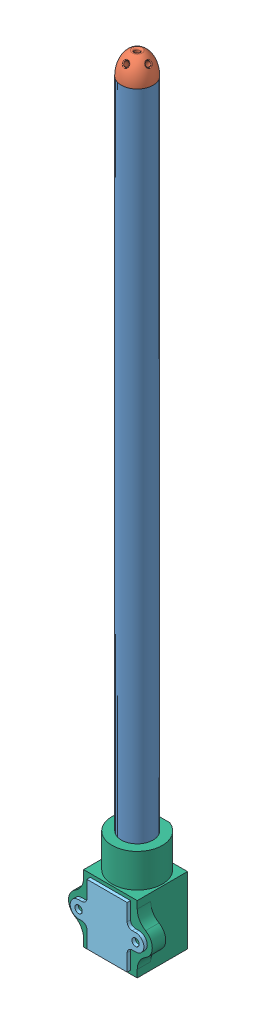
SolidWorks assembly flow-sensor, configuration Default. Lengths in mm.
Overall size (25 231.71 16).
9 component instances, 6 part files, 6 mates.
Components (placement in the parent):
- flow-sensor-tube-1: flow-sensor-tube [Default] at origin size (9.5 200 9.5)
- flow-sensor-tip-1: flow-sensor-tip [Default] at (0 200 0) x (1 0 0) z (0 -1 0) size (9.5 9.5 9.71)
- pressure_board-1: pressure_board [Default] at (0 -15 8) x (0 1 0) z (-1 0 0) size (30 16 25)
  - sdp3x-1: sdp3x [Default] at (4.5 0 3) size (8.5 4.4 5.5)
  - sdp3x-2: sdp3x [Default] at (4.5 0 -3) x (-1 0 0) z (0 0 -1) size (8.5 4.4 5.5)
  - sdp3x-3: sdp3x [Default] at (-4.5 0 3) size (8.5 4.4 5.5)
  - static_pressure_connector-1: static_pressure_connector [Default] at (-4.5 0 -3) size (8 6.1 9.55)
  - PCB^pressure_board-1: PCB^pressure_board [Default] at origin size (18 1 22) (virtual)
  - Part2^pressure_board-1: Part2^pressure_board [Default] at origin size (30 15 25) (virtual)
Mates (geometry in assembly coordinates):
- Coincident1: coincident anti-aligned: circle of flow-sensor-tube-1; circle of flow-sensor-tip-1
- Concentric1: concentric anti-aligned: cylinder of flow-sensor-tube-1 through (0 200 0) axis (0 -1 0) radius 4.75; cylinder of pressure_board-1/Part2^pressure_board-1 through (0 -19.435 0) axis (0 1 0) radius 4.75
- Coincident2: coincident anti-aligned: plane of flow-sensor-tube-1 through (0 0 0) normal (0 -1 0); plane of pressure_board-1/Part2^pressure_board-1 through (5.6615 0 1.9869) normal (0 1 0)
- Coincident3: coordinate: point of flow-sensor-tube-1; point of assembly
- Coincident4: coincident aligned: plane of flow-sensor-tip-1 through (0 200 0) normal (0 0 1); plane of assembly
- Parallel1: parallel anti-aligned: plane of ? through (0 -15 8) normal (0 0 -1)
